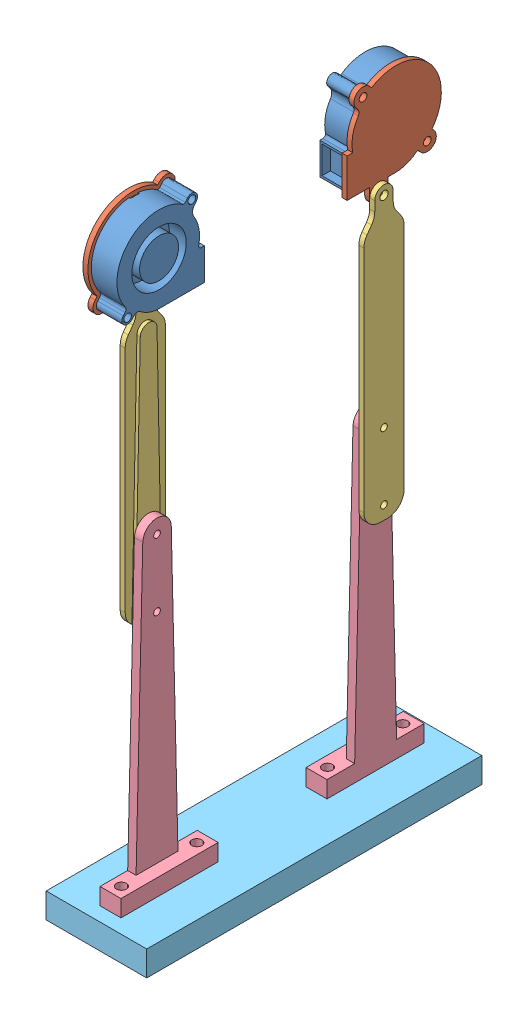
SolidWorks assembly CentrifugalCooling Assembly, configuration Default. Lengths in mm.
Overall size (60 375.55 200).
9 component instances, 5 part files, 27 mates.
Components (placement in the parent):
- Centrifugal-fan-1: Centrifugal-fan [Default] at (15.3 19 -50) x (0 0 -1) z (0 1 0) size (52.24 15.3 51.2)
- CentrifugalFan-Bracket-1: CentrifugalFan-Bracket [Default] at (15.3 19 -50) x (0 0 1) z (1 0 0) size (56.24 66.05 3)
- CentrifugalFan-HeightArm-1: CentrifugalFan-HeightArm [Default] at origin size (5 173.5 24)
- CentrifugalFan-Base-1: CentrifugalFan-Base [Default] at (16.3 0 0) x (0 0 1) z (-1 0 0) size (58 188.5 12.5)
- CentrifugalCooling-WoodBase-1: CentrifugalCooling-WoodBase [Default] at (10.05 -322.3539 -6.64) x (0 0 1) z (-1 0 0) size (200 15 60)
- CentrifugalFan-Base-3: CentrifugalFan-Base [Default] at (3.8 0 -11.03) x (0 0 -1) z (1 0 0) size (58 188.5 12.5)
- CentrifugalFan-HeightArm-3: CentrifugalFan-HeightArm [Default] at (20.1 0 -11.03) x (-1 0 0) z (0 0 -1) size (5 173.5 24)
- CentrifugalFan-Bracket-3: CentrifugalFan-Bracket [Default] at (4.8 19 38.97) x (0 0 -1) z (-1 0 0) size (56.24 66.05 3)
- Centrifugal-fan-4: Centrifugal-fan [Default] at (4.8 19 38.97) x (0 0 1) z (0 1 0) size (52.24 15.3 51.2)
Mates (geometry in assembly coordinates):
- Distance1: distance = 50 mm aligned: plane of Centrifugal-fan-1 through (0 19 -50) normal (0 0 1)
- Coincident6: coincident anti-aligned: plane of Centrifugal-fan-1 through (0 20.7509 -51.76) normal (-1 0 0)
- Coincident7: coincident anti-aligned: plane of Centrifugal-fan-1 through (0 0 -50) normal (0 -1 0)
- InPlace1: in place: plane of Centrifugal-fan-1 through (15.3 20.7509 -51.76) normal (1 0 0); plane of ? through (15.3 0 0) normal (1 0 0); moOrthogonalPlaneRef_w of Centrifugal-fan-1 through (15.3 20.7509 -51.76) normal (1 0 0); plane of ? through (15.3 0 0) normal (0 1 0); plane of Centrifugal-fan-1 through (15.3 20.7509 -51.76) normal (1 0 0); plane of ? through (15.3 0 0) normal (0 0 -1); plane of Centrifugal-fan-1 through (15.3 20.7509 -51.76) normal (1 0 0); unknown of CentrifugalFan-Bracket-1
- Coincident8: coincident aligned: plane of Centrifugal-fan-1; plane of CentrifugalFan-Bracket-1
- Coincident9: coincident aligned: moOrthogonalPlaneRef_w of Centrifugal-fan-1 through (15.3 19 -50) normal (0 -1 0); plane of Part1^CentrifugalCooling Assembly-1 through (15.3 19 -50) normal (0 -1 0)
- Coincident10: coincident anti-aligned: moOrthogonalPlaneRef_w of Centrifugal-fan-1 through (15.3 19 -50) normal (0 0 -1); plane of Part1^CentrifugalCooling Assembly-1 through (15.3 19 -50) normal (0 0 1)
- InPlace2: in place: plane of CentrifugalFan-HeightArm-1 through (16.3 -25.3539 -67) normal (-1 0 0); plane of CentrifugalFan-Base-1 through (16.3 0 0) normal (-1 0 0); plane of CentrifugalFan-HeightArm-1 through (16.3 -25.3539 -67) normal (-1 0 0); plane of CentrifugalFan-Base-1 through (16.3 0 0) normal (0 1 0); plane of CentrifugalFan-HeightArm-1 through (16.3 -25.3539 -67) normal (-1 0 0); plane of CentrifugalFan-Base-1 through (16.3 0 0) normal (0 0 1); plane of CentrifugalFan-HeightArm-1 through (16.3 -25.3539 -67) normal (-1 0 0); unknown of CentrifugalFan-Base-1
- Coincident11: coincident aligned: plane of CentrifugalFan-HeightArm-1; plane of CentrifugalFan-Base-1
- Coincident12: coincident aligned: moOrthogonalPlaneRef_w of CentrifugalFan-HeightArm-1 through (16.3 0 0) normal (0 1 0); plane of CentrifugalFan-Base-1 through (16.3 0 0) normal (0 1 0)
- Coincident13: coincident anti-aligned: moOrthogonalPlaneRef_w of CentrifugalFan-HeightArm-1 through (16.3 0 0) normal (0 0 -1); plane of CentrifugalFan-Base-1 through (16.3 0 0) normal (0 0 1)
- Coincident11: coincident anti-aligned: plane of CentrifugalFan-Base-1 through (11.3 -307.3539 -96) normal (0 -1 0); plane of CentrifugalCooling-WoodBase-1 through (10.05 -307.3539 -6.64) normal (0 1 0)
- Parallel1: parallel anti-aligned: line of CentrifugalCooling-WoodBase-1 through (40.05 -307.3539 -81.64) axis (-1 0 0); line of CentrifugalFan-Base-1 through (3.8 -307.3539 -38) axis (1 0 0)
- Coincident12: coincident: point of CentrifugalFan-Base-1; line of CentrifugalCooling-WoodBase-1 through (10.05 -307.3539 -106.64) axis (0 0 1)
- Coincident15: coincident anti-aligned: plane of CentrifugalCooling-WoodBase-1 through (10.05 -307.3539 -6.64) normal (0 1 0); plane of CentrifugalFan-Base-3 through (8.8 -307.3539 84.97) normal (0 -1 0)
- Coincident16: coincident: line of CentrifugalCooling-WoodBase-1 through (10.05 -307.3539 -106.64) axis (0 0 1); unknown of CentrifugalFan-Base-3
- Distance3: distance = 8.39 mm aligned: plane of CentrifugalFan-Base-3 through (8.8 -297.3539 84.97) normal (0 0 1); plane of CentrifugalCooling-WoodBase-1 through (-19.95 -307.3539 93.36) normal (0 0 1)
- Coincident18: coincident anti-aligned: plane of CentrifugalFan-Base-3 through (3.8 -127.3539 55.97) normal (-1 0 0); plane of CentrifugalFan-HeightArm-3 through (3.8 -25.3539 55.97) normal (1 0 0)
- Concentric1: concentric aligned: circle of CentrifugalFan-Base-3; circle of CentrifugalFan-HeightArm-3
- Concentric2: concentric aligned: circle of CentrifugalFan-Base-3; circle of CentrifugalFan-HeightArm-3
- Coincident21: coincident anti-aligned: plane of CentrifugalFan-HeightArm-3 through (1.8 -7.3539 55.97) normal (1 0 0); plane of CentrifugalFan-Bracket-3 through (1.8 -7.3539 55.97) normal (-1 0 0)
- Concentric3: concentric aligned: cylinder of CentrifugalFan-HeightArm-3 through (-1.2 -7.3539 55.97) axis (1 0 0) radius 2.5; cylinder of CentrifugalFan-Bracket-3 through (1.8 -7.3539 55.97) axis (1 0 0) radius 2.5
- Distance5: distance = 10.64 mm aligned: plane of CentrifugalFan-Base-1 through (11.3 -297.3539 -96) normal (0 0 -1); plane of CentrifugalCooling-WoodBase-1 through (-19.95 -307.3539 -106.64) normal (0 0 -1)
- Coincident25: coincident anti-aligned: plane of CentrifugalFan-Bracket-3 through (4.8 -7.3539 55.97) normal (1 0 0); plane of Centrifugal-fan-4 through (-7.8227 21.0966 35.9241) normal (-1 0 0)
- Coincident26: coincident anti-aligned: circle of CentrifugalFan-Bracket-3; cylinder of Centrifugal-fan-4 through (-7.8227 13.2508 82.176) axis (1 0 0) radius 2.3
- Coincident27: coincident anti-aligned: circle of CentrifugalFan-Bracket-3; cylinder of Centrifugal-fan-4 through (-7.8227 47.5445 36.9393) axis (1 0 0) radius 2.3
- Parallel5: parallel anti-aligned: plane of Centrifugal-fan-1 through (0 19 -50) normal (0 0 1); plane of Centrifugal-fan-4 through (20.1 19 38.97) normal (0 0 -1)
